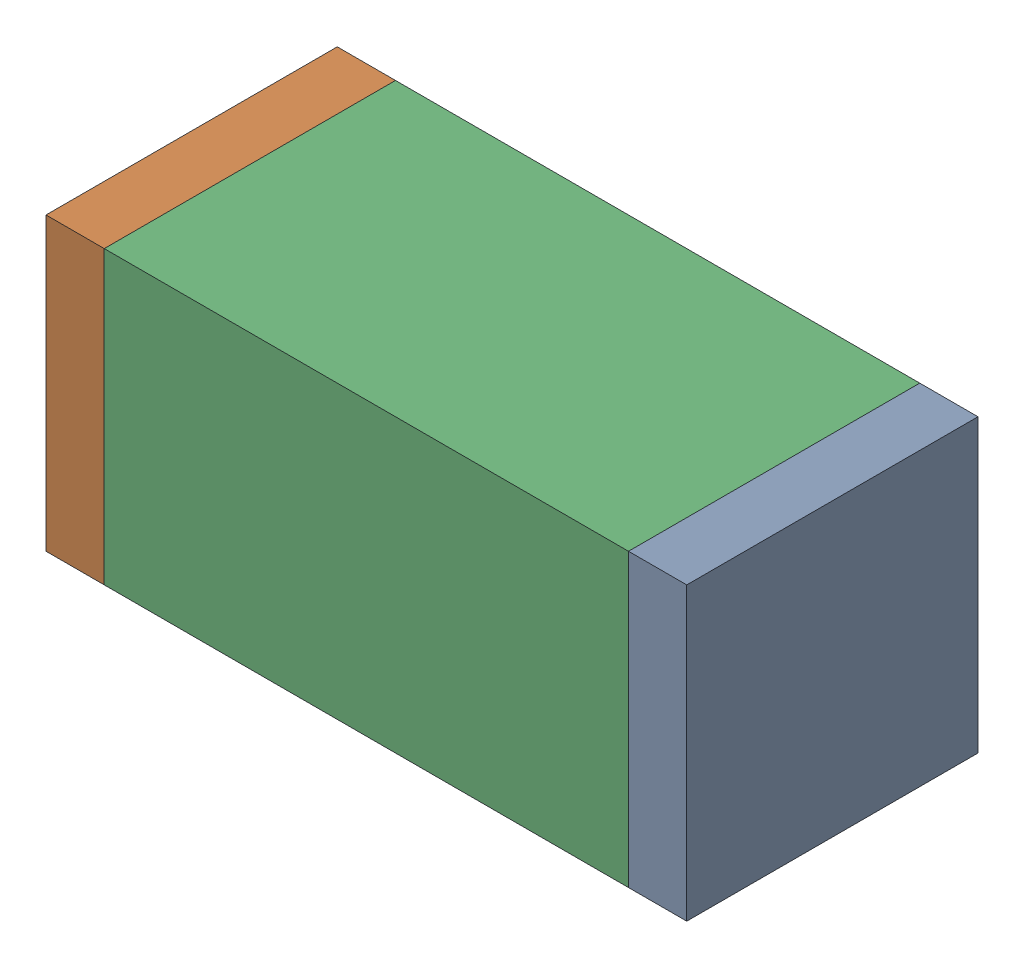
SolidWorks assembly R82, configuration Default. Lengths in mm.
Overall size (1.1 0.5 0.5).
6 component instances, 2 part files, 0 mates.
Components (placement in the parent):
- 810156080-1: 810156080 [Default] at (133.75 29.7 0) size (0.1 0.5 0.5)
  - Extruded_5-1: Extruded_5 [Default] at origin size (0.1 0.5 0.5)
- 810156080-2: 810156080 [Default] at (132.75 29.7 0) size (0.1 0.5 0.5)
  - Extruded_5-1: Extruded_5 [Default] at origin size (0.1 0.5 0.5)
- 836749680-1: 836749680 [Default] at (133.25 29.7 0) size (0.9 0.5 0.5)
  - Extruded_4-1: Extruded_4 [Default] at origin size (0.9 0.5 0.5)
